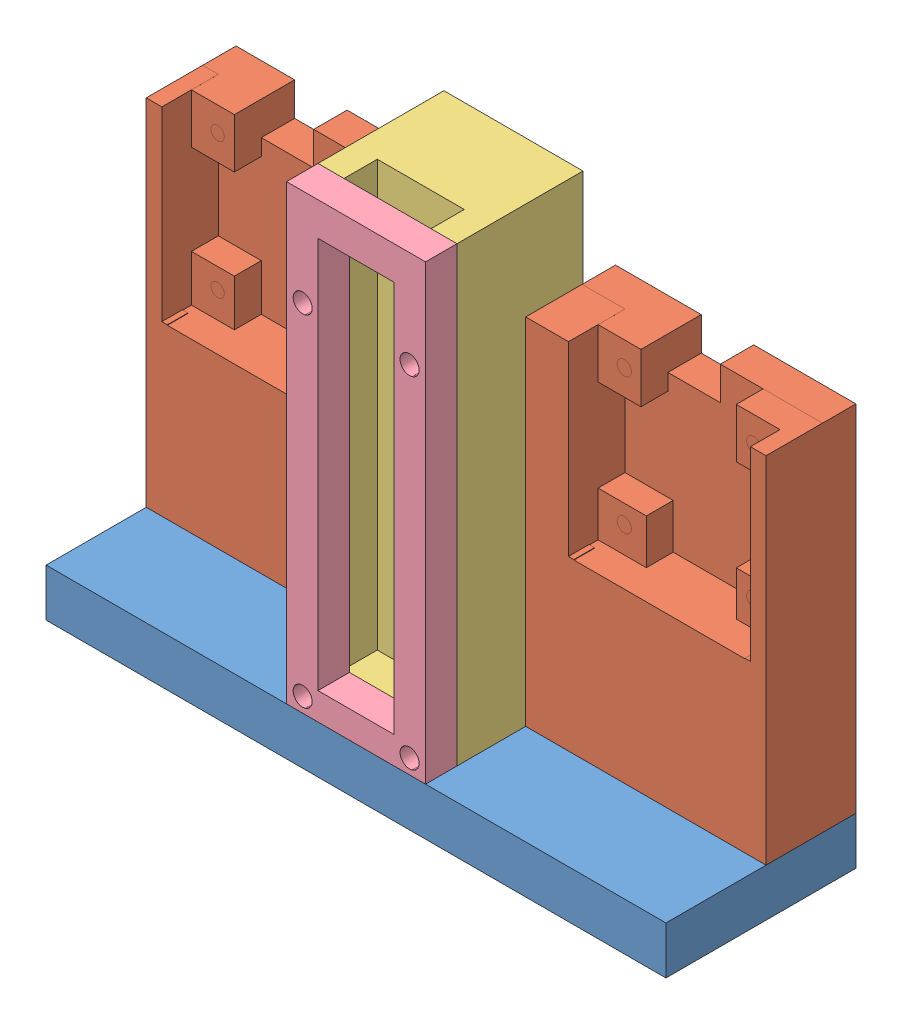
SolidWorks assembly PMD Webcam mount v2, configuration Default. Lengths in mm.
Overall size (130 104.86 39.84).
5 component instances, 4 part files, 6 mates.
Components (placement in the parent):
- Camera mount baseplate v2-1: Camera mount baseplate v2 [Default] at (-17.0824 59.2089 122.4946) size (130 10 39.84)
- webcam holder heat sink-1: webcam holder heat sink [Default] at (47.9176 42.5716 81.4955) size (130 74.36 18.84)
- PMD heat sink complete-1: PMD heat sink complete [Default] at (59.1285 80.8311 -18.1111) size (29.16 94.86 33.01)
  - PMD camera holder heat sink-1: PMD camera holder heat sink [Default] at (-11.2109 -38.2595 99.4357) size (29.16 94.86 26.41)
  - PMD heat sink front face-1: PMD heat sink front face [Default] at (3.3691 -11.6195 134.0057) size (29.16 94.86 6.69)
Mates (geometry in assembly coordinates):
- Coincident1: coincident aligned: plane of Camera mount baseplate v2-1 through (112.9176 69.2089 122.4946) normal (1 0 0); plane of webcam holder heat sink-1 through (112.9176 143.5689 89.6546) normal (1 0 0)
- Coincident3: coincident anti-aligned: plane of Camera mount baseplate v2-1 through (-17.0824 69.2089 122.4946) normal (0 1 0); plane of webcam holder heat sink-1 through (-17.0824 69.2089 61.4955) normal (0 -1 0)
- Coincident4: coincident aligned: plane of Camera mount baseplate v2-1 through (-17.0824 69.2089 82.6546) normal (0 0 -1); plane of webcam holder heat sink-1 through (112.9176 143.5689 82.6546) normal (0 0 -1)
- Coincident5: coincident anti-aligned: plane of Camera mount baseplate v2-1 through (-17.0824 69.2089 122.4946) normal (0 1 0); plane of PMD heat sink complete-1/PMD camera holder heat sink-1 through (-17.0824 69.2089 61.3246) normal (0 -1 0)
- Coincident6: coincident anti-aligned: plane of webcam holder heat sink-1 through (62.4976 143.5689 89.6546) normal (-1 0 0); plane of PMD heat sink complete-1/PMD camera holder heat sink-1 through (62.4976 117.5716 117.3946) normal (1 0 0)
- Coincident8: coincident aligned: plane of Camera mount baseplate v2-1 through (-17.0824 69.2089 122.4946) normal (0 0 1); plane of PMD heat sink complete-1/PMD heat sink front face-1 through (62.4976 69.2116 122.4946) normal (0 0 1)
